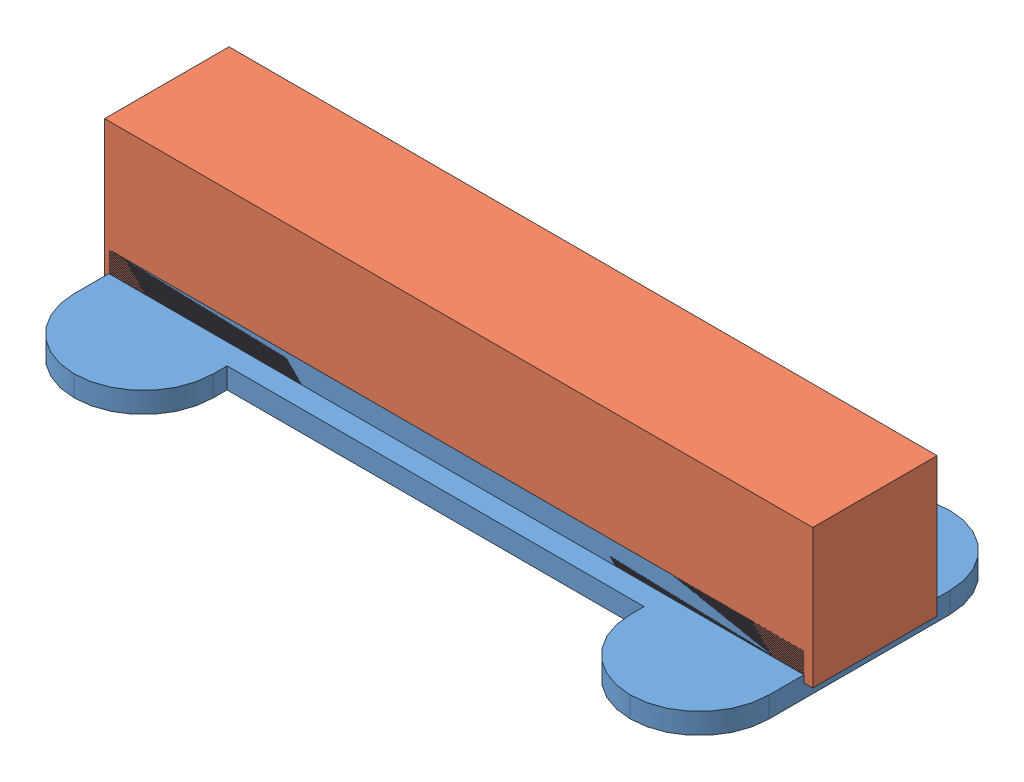
SolidWorks assembly Assem1, configuration Default. Lengths in mm.
Overall size (101.9 22 46).
2 component instances, 2 part files, 2 mates.
Components (placement in the parent):
- SR_oct29_Male-1: SR_oct29_Male [Default] at (-83.7903 -9.7286 26.3257) size (100 18 46)
- SR_oct29_negativeblock-1: SR_oct29_negativeblock [Default] at (-34.1486 -7.7286 11.1387) size (101.9 20 17.9)
Mates (geometry in assembly coordinates):
- Coincident1: coincident: plane of SR_oct29_Male-1 through (-83.7903 -7.7286 26.3257) normal (0 1 0); plane of SR_oct29_negativeblock-1 through (-34.1486 -7.7286 11.1387) normal (0 -1 0)
- Coincident2: coincident: plane of SR_oct29_Male-1 through (-83.7903 -3.7286 26.3257) normal (0 0 1); plane of SR_oct29_negativeblock-1 through (-84.4112 12.2714 26.3257) normal (0 0 1)
